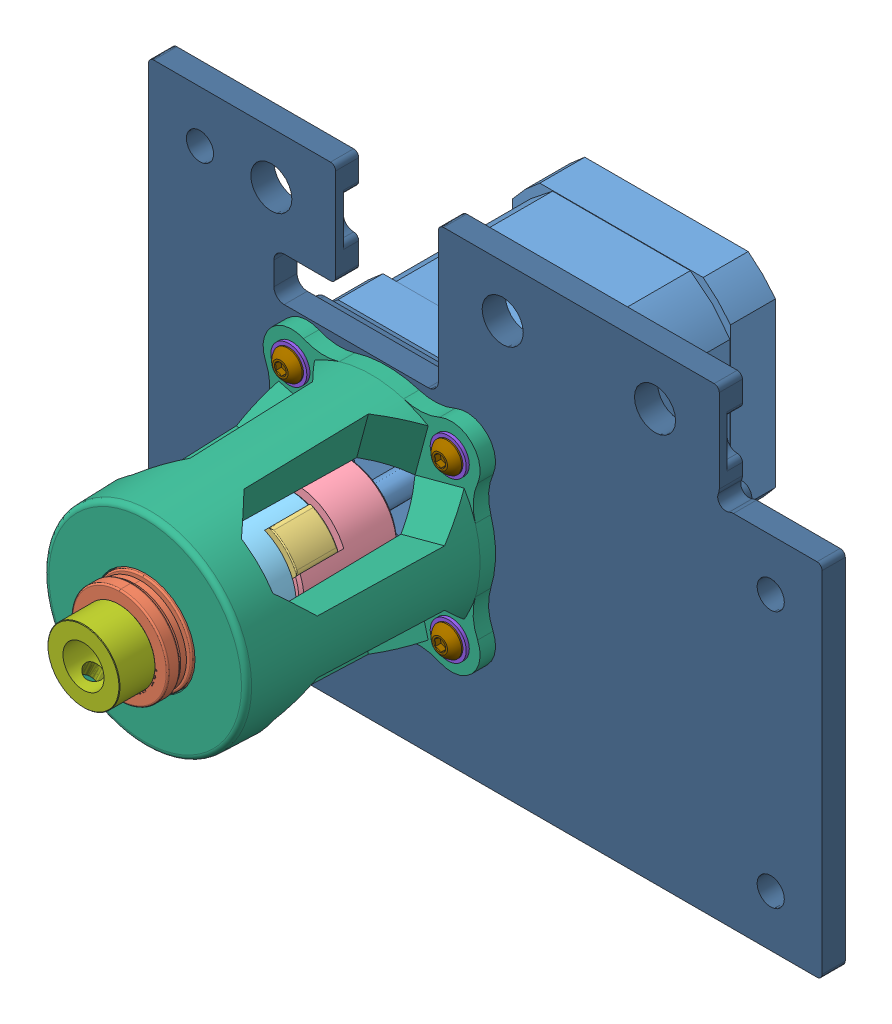
SolidWorks assembly machined_front_z_motor_plate_assy, configuration right. Lengths in mm.
Overall size (131 90 113.35).
19 component instances, 10 part files, 6 mates.
Components (placement in the parent):
- z-motor_thrust_assembly-1: z-motor_thrust_assembly [Default] at (19.0713 66.7435 94.6612) x (0 -1 0) z (0 0 -1) size (42.42 42.42 113.35)
  - 17HM19-2004S-1: 17HM19-2004S [Default] at (0 -11.5 6.35) x (1 0 0) z (0 0 -1) size (42.42 42.42 72)
  - AST_Bearings_F8-19M-1: AST_Bearings_F8-19M [Default] at (-0.0375 -11.4625 -48.5) x (1 0 0) z (0 1 0) size (19 7 19)
  - couplings_cajc20-rd-5-8-1: couplings_cajc20-rd-5-8 [Default] at (0 -11.5 -22.65) x (0 0 -1) z (1 0 0) size (30 20 20)
    - couplings_cajc20-rd-5-8_01-1: couplings_cajc20-rd-5-8_01 [Default] at origin size (8 18.12 18.12)
    - couplings_cajc20-rd-5-8_02-1: couplings_cajc20-rd-5-8_02 [Default] at origin size (19 20 19.99)
    - couplings_cajc20-rd-5-8_03-1: couplings_cajc20-rd-5-8_03 [Default] at origin size (19 19.99 20)
  - thrust_cage-1: thrust_cage [Default] at (-0.0375 -11.4625 -15.6528) x (1 0 0) z (0 1 0) size (42.3 47 42.3)
  - T8_lock_collar-1: T8_lock_collar [Default] at (-0.0375 -11.4625 -59) x (0 1 0) z (1 0 0) size (14 7 14)
  - m3_stainless_steel_washer_90965A130-1: m3_stainless_steel_washer_90965A130 [90965A130] at (15.5 4 -3) x (0.923728 0.383049 0) z (0 0 -1) size (7 7 0.6)
  - m3_12mm_buttohead_screw_92095A183-1: m3_12mm_buttohead_screw_92095A183 [92095A183] at (15.5 4 -5.25) x (0.923728 0.383049 0) z (0 0 -1) size (5.7 5.7 13.97)
  - m3_stainless_steel_washer_90965A130-2: m3_stainless_steel_washer_90965A130 [90965A130] at (-15.5 4 -3) x (0.923728 0.383049 0) z (0 0 -1) size (7 7 0.6)
  - m3_stainless_steel_washer_90965A130-3: m3_stainless_steel_washer_90965A130 [90965A130] at (15.5 -27 -3) x (0.923728 0.383049 0) z (0 0 -1) size (7 7 0.6)
  - m3_stainless_steel_washer_90965A130-4: m3_stainless_steel_washer_90965A130 [90965A130] at (-15.5 -27 -3) x (0.923728 0.383049 0) z (0 0 -1) size (7 7 0.6)
  - m3_12mm_buttohead_screw_92095A183-2: m3_12mm_buttohead_screw_92095A183 [92095A183] at (15.5 -27 -5.25) x (0.923728 0.383049 0) z (0 0 -1) size (5.7 5.7 13.97)
  - m3_12mm_buttohead_screw_92095A183-3: m3_12mm_buttohead_screw_92095A183 [92095A183] at (-15.5 -27 -5.25) x (0.923728 0.383049 0) z (0 0 -1) size (5.7 5.7 13.97)
  - m3_12mm_buttohead_screw_92095A183-5: m3_12mm_buttohead_screw_92095A183 [92095A183] at (-15.5 4 -5.25) x (0.923728 0.383049 0) z (0 0 -1) size (5.7 5.7 13.97)
- machined_front_z_motor_plate-1: machined_front_z_motor_plate [Right] at (49.6963 71.7435 94.6612) size (131 90 6.35)
- machined_front_z_motor_plate-2: machined_front_z_motor_plate [Left] at (49.6963 61.7435 94.6612) x (1 0 0) z (0 0 -1) size (131 90 6.35) (hidden)
Mates (geometry in assembly coordinates):
- Concentric1: concentric anti-aligned: cylinder of machined_front_z_motor_plate-1 through (30.5713 66.7435 94.6612) axis (0 0 1) radius 12.5; cylinder of z-motor_thrust_assembly-1/17HM19-2004S-1 through (30.5713 66.7435 90.3112) axis (0 0 -1) radius 11
- Concentric2: concentric aligned: cylinder of machined_front_z_motor_plate-1 through (46.0713 51.2435 88.3112) axis (0 0 1) radius 1.5875; cylinder of z-motor_thrust_assembly-1/thrust_cage-1 through (46.0713 51.2435 97.6612) axis (0 0 1) radius 1.7
- Concentric3: concentric aligned: cylinder of machined_front_z_motor_plate-1 through (15.0713 82.2435 88.3112) axis (0 0 1) radius 1.5875; cylinder of z-motor_thrust_assembly-1/thrust_cage-1 through (15.0713 82.2435 97.6612) axis (0 0 1) radius 1.7
- Coincident3: coincident anti-aligned: plane of z-motor_thrust_assembly-1/17HM19-2004S-1 through (30.5713 66.7435 88.3112) normal (0 0 1); plane of machined_front_z_motor_plate-2 through (49.6963 61.7435 88.3112) normal (0 0 -1)
- Concentric6: concentric anti-aligned: circle of z-motor_thrust_assembly-1/m3_12mm_buttohead_screw_92095A183-5; cylinder of machined_front_z_motor_plate-2 through (15.0713 82.2435 88.3112) axis (0 0 -1) radius 1.5875
- Concentric7: concentric anti-aligned: circle of z-motor_thrust_assembly-1/m3_12mm_buttohead_screw_92095A183-2; cylinder of machined_front_z_motor_plate-2 through (46.0713 51.2435 88.3112) axis (0 0 -1) radius 1.5875
